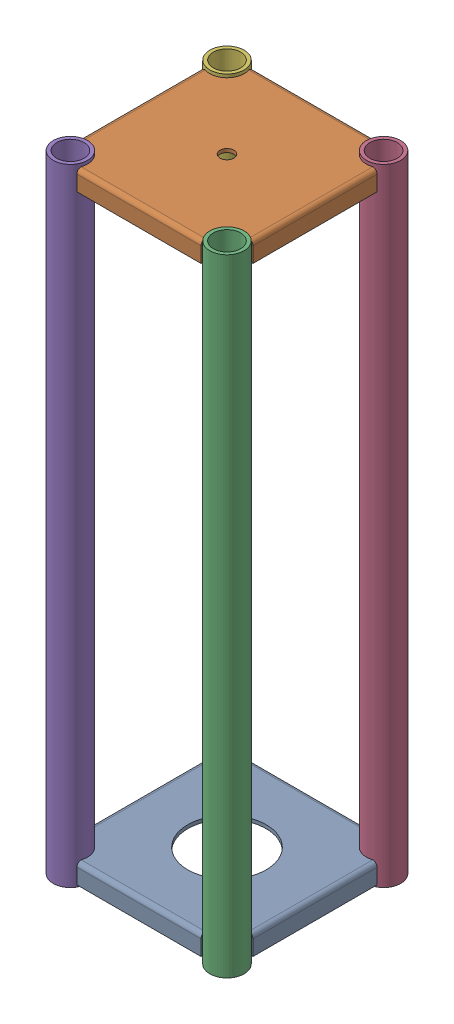
SolidWorks assembly GE-25201, configuration Default. Lengths in mm.
Overall size (185.8 609.6 185.8).
6 component instances, 3 part files, 17 mates.
Components (placement in the parent):
- GE-25201-01-1: GE-25201-01 [Default] at (0 22.225 0) size (171.42 19.05 171.42)
- GE-25201-02-1: GE-25201-02 [Default] at (0 606.425 0) size (171.42 19.05 171.42)
- GE-25201-03-1: GE-25201-03 [Default] at (76.2 0 76.2) size (33.4 609.6 33.4)
- GE-25201-03-2: GE-25201-03 [Default] at (76.2 0 -76.2) size (33.4 609.6 33.4)
- GE-25201-03-3: GE-25201-03 [Default] at (-76.2 0 76.2) size (33.4 609.6 33.4)
- GE-25201-03-4: GE-25201-03 [Default] at (-76.2 0 -76.2) size (33.4 609.6 33.4)
Mates (geometry in assembly coordinates):
- Coincident1: coincident aligned: plane of shortie_m6-01-1 through (0 22.225 0) normal (0 0 1)
- Coincident2: coincident aligned: plane of shortie_m6-01-1 through (0 22.225 0) normal (1 0 0)
- Coincident3: coincident aligned: plane of shortie_m6-01-1 through (0 22.225 85.7123) normal (0 0 1); plane of shortie_m6-02-1 through (0 606.425 85.7123) normal (0 0 1)
- Coincident4: coincident aligned: plane of shortie_m6-01-1 through (85.7123 22.225 0) normal (1 0 0); plane of shortie_m6-02-1 through (85.7123 606.425 0) normal (1 0 0)
- Distance1: distance = 603.25 mm anti-aligned: plane of shortie_m6-02-1 through (76.2 606.425 76.2) normal (0 1 0); plane of shortie_m6-01-1 through (-60.3828 3.175 85.7123) normal (0 -1 0)
- Concentric1: concentric anti-aligned: cylinder of shortie_m6-02-1 through (-76.2 603.0087 76.2) axis (0 1 0) radius 16.7005; cylinder of shortie_m6-03-3 through (-76.2 609.6 76.2) axis (0 -1 0) radius 16.7005
- Distance2: distance = 3.175 mm aligned: plane of shortie_m6-03-3 through (-76.2 609.6 76.2) normal (0 1 0); plane of shortie_m6-02-1 through (76.2 606.425 76.2) normal (0 1 0)
- Concentric2: concentric anti-aligned: cylinder of shortie_m6-02-1 through (76.2 603.0087 76.2) axis (0 1 0) radius 16.7005; cylinder of shortie_m6-03-1 through (76.2 609.6 76.2) axis (0 -1 0) radius 16.7005
- Coincident7: coincident aligned: plane of shortie_m6-03-1 through (76.2 609.6 76.2) normal (0 1 0); plane of shortie_m6-03-3 through (-76.2 609.6 76.2) normal (0 1 0)
- Concentric3: concentric anti-aligned: cylinder of shortie_m6-02-1 through (76.2 603.0087 -76.2) axis (0 1 0) radius 16.7005; cylinder of shortie_m6-03-2 through (76.2 609.6 -76.2) axis (0 -1 0) radius 16.7005
- Coincident8: coincident aligned: plane of shortie_m6-03-1 through (76.2 609.6 76.2) normal (0 1 0); plane of shortie_m6-03-2 through (76.2 609.6 -76.2) normal (0 1 0)
- Concentric4: concentric anti-aligned: line of shortie_m6-02-1 through (-76.2 603.0087 -76.2) axis (0 1 0); axis of shortie_m6-03-4 through (-76.2 609.6 -76.2) axis (0 -1 0)
- Coincident9: coincident aligned: plane of shortie_m6-03-2 through (76.2 609.6 -76.2) normal (0 1 0); plane of shortie_m6-03-4 through (-76.2 609.6 -76.2) normal (0 1 0)
- Coincident10: coincident anti-aligned: plane of shortie_m6-03-1 through (76.2 0 76.2) normal (0 -1 0)
- Coincident11: coincident anti-aligned: plane of shortie_m6-03-3 through (-76.2 0 76.2) normal (0 -1 0)
- Coincident12: coincident anti-aligned: plane of shortie_m6-03-4 through (-76.2 0 -76.2) normal (0 -1 0)
- Coincident13: coincident anti-aligned: plane of shortie_m6-03-2 through (76.2 0 -76.2) normal (0 -1 0)
